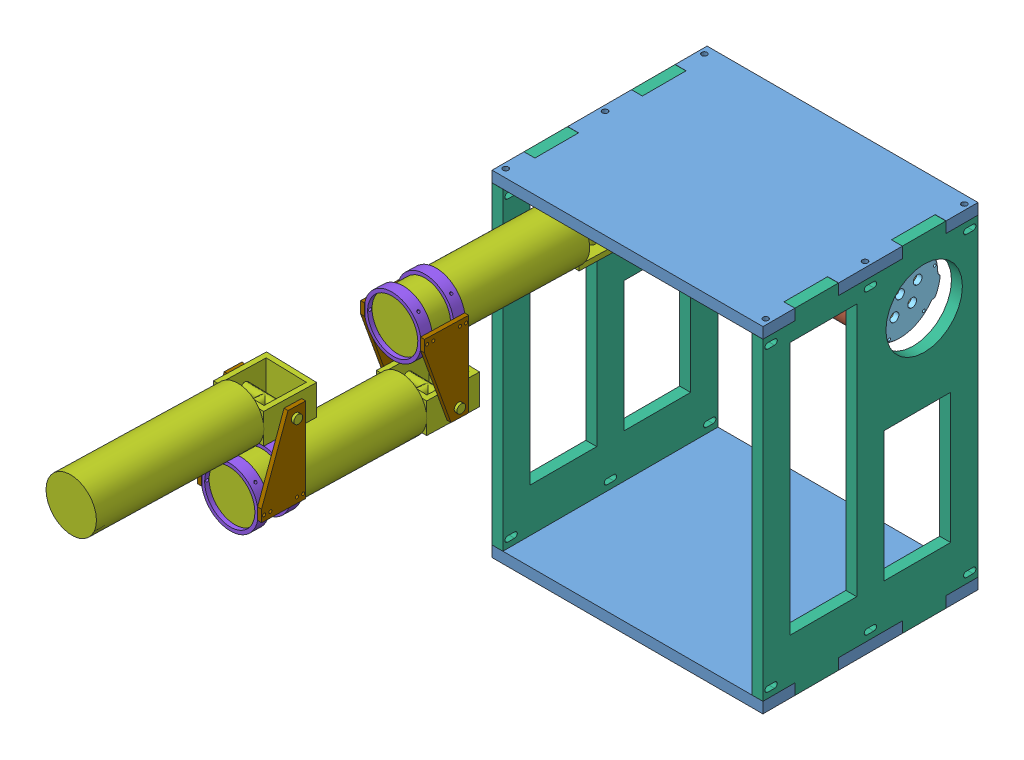
SolidWorks assembly EnsamblajeRobotC_Movimiento_Long, configuration Predeterminado. Lengths in mm.
Overall size (320.46 390 780.45).
23 component instances, 9 part files, 18 mates.
Components (placement in the parent):
- TP_Base-1: TP_Base [Predeterminado] at origin size (315 12.7 250)
- EnsambleTubo-1: EnsambleTubo [Predeterminado] at (117.3931 -62.5 -62.4) x (1 0 0) z (0 0.206267 0.978496) size (292.35 100.44 103.58)
  - WTE3-P-LOCKING-TUBE-240-R2-1: WTE3-P-LOCKING-TUBE-240-R2 [Predeterminado] at origin size (240.01 88.9 88.9)
  - WTE3-M-LOCKING-FLANGE-SEAL-R1-RP-1: WTE3-M-LOCKING-FLANGE-SEAL-R1-RP [Predeterminado] at (-21 0 0) x (0 0 -1) z (1 0 0) size (88.9 95.83 27.56)
  - WTE3-M-LOCKING-FLANGE-SEAL-R1-RP-2: WTE3-M-LOCKING-FLANGE-SEAL-R1-RP [Predeterminado] at (-219 0 0) x (0 0 1) z (-1 0 0) size (88.9 95.83 27.56)
  - WTE3-P-DOME-R1-1: WTE3-P-DOME-R1 [Default] at (-246 0 0) x (0 0.996902 0.078658) z (0 -0.078658 0.996902) size (79.25 34.35 79.25)
  - WTE3-M-END-CAP-7-HOLE-R1-1: WTE3-M-END-CAP-7-HOLE-R1 [Default] at (6 0 0) x (0 -0.102065 -0.994778) z (1 0 0) size (95 88.9 6)
- TP_Base-2: TP_Base [Predeterminado] at (0 -377.3 0.1) size (315 12.7 250)
- Side_Base_Long-1: Side_Base_Long [Predeterminado] at (-157.5 -182.3 0.1) x (0 0 -1) z (1 0 0) size (250 390 12.7)
- Side_Base_Long-2: Side_Base_Long [Predeterminado] at (144.8 -182.3 0.1) x (0 0 -1) z (1 0 0) size (250 390 12.7)
- EslabonVertical-1: EslabonVertical [Predeterminado] at (-104.5 -39.75 63) x (0 -1 0) z (-0.027267 0 0.999628) size (140.08 96.17 254.65)
  - EslabonSimplificado-1: EslabonSimplificado [Predeterminado] at origin size (79.5 60.33 249.5)
  - SujeccionMotorV2-1: SujeccionMotorV2 [Predeterminado] at (0 0 181) x (0.707107 -0.707107 0) z (0 0 1) size (68 68 12.7)
  - Soporte-1: Soporte [Predeterminado] at (-6.35 -38.1643 174.65) x (0 0 -1) z (0 1 0) size (50 98.35 4.76)
  - SujeccionMotorV2-2: SujeccionMotorV2 [Predeterminado] at (0 0 218.15) x (0.707107 -0.707107 0) z (0 0 1) size (68 68 12.7)
  - Soporte-2: Soporte [Predeterminado] at (-6.35 33.4018 174.65) x (0 0 -1) z (0 1 0) size (50 98.35 4.76)
- EslabonHorizontal-1: EslabonHorizontal [Predeterminado] at (-107.9866 -120.4 248.9741) x (0.999628 0 0.027267) z (-0.027267 0 0.999628) size (96.17 140.08 254.65)
  - EslabonSimplificado-1: EslabonSimplificado [Predeterminado] at origin size (79.5 60.33 249.5)
  - SujeccionMotorV2-1: SujeccionMotorV2 [Predeterminado] at (0 0 181) x (0.707107 0.707107 0) z (0 0 1) size (68 68 12.7)
  - Soporte-1: Soporte [Predeterminado] at (38.1643 -6.35 174.65) x (0 0 -1) z (-1 0 0) size (50 98.35 4.76)
  - SujeccionMotorV2-2: SujeccionMotorV2 [Predeterminado] at (0 0 218.15) x (0.707107 0.707107 0) z (0 0 1) size (68 68 12.7)
  - Soporte-2: Soporte [Predeterminado] at (-33.4018 -6.35 174.65) x (0 0 -1) z (-1 0 0) size (50 98.35 4.76)
- EslabonSimplificado-1: EslabonSimplificado [Predeterminado] at (-111.4732 -39.75 434.9482) x (0.999628 0 0.027267) z (-0.027267 0 0.999628) size (79.5 60.33 249.5)
Mates (geometry in assembly coordinates):
- Coincidente1: coincident anti-aligned: plane of TP_Base-1 through (-144.8 0 -87.9) normal (-1 0 0); plane of Side_Base_Long-1 through (-144.8 -182.3 0.1) normal (1 0 0)
- Coincidente2: coincident anti-aligned: plane of TP_Base-1 through (-157.5 0 -37.1) normal (0 0 -1); plane of Side_Base_Long-1 through (-157.5 12.7 -37.1) normal (0 0 1)
- Coincidente3: coincident aligned: plane of TP_Base-1 through (0 12.7 0) normal (0 1 0); plane of Side_Base_Long-1 through (-144.8 12.7 125.1) normal (0 1 0)
- Concéntrica1: concentric aligned: cylinder of EnsambleTubo-1/WTE3-P-LOCKING-TUBE-240-R2-1 through (41.1931 -62.5 -62.4) axis (-1 0 0) radius 44.45; cylinder of Side_Base_Long-1 through (-144.8 -62.5 -62.4) axis (-1 0 0) radius 44.5
- Coincidente4: coincident anti-aligned: plane of TP_Base-1 through (144.8 0 -87.9) normal (1 0 0); plane of Side_Base_Long-2 through (144.8 -182.3 0.1) normal (-1 0 0)
- Coincidente5: coincident anti-aligned: plane of TP_Base-1 through (157.5 0 87.9) normal (0 0 -1); plane of Side_Base_Long-2 through (144.8 12.7 87.9) normal (0 0 1)
- Coincidente6: coincident aligned: plane of TP_Base-1 through (0 12.7 0) normal (0 1 0); plane of Side_Base_Long-2 through (157.5 12.7 125.1) normal (0 1 0)
- Coincidente7: coincident anti-aligned: plane of TP_Base-2 through (0 -364.6 0.1) normal (0 1 0); plane of Side_Base_Long-2 through (144.8 -364.6 125.1) normal (0 -1 0)
- Coincidente8: coincident aligned: plane of TP_Base-2 through (157.5 -364.6 125.1) normal (1 0 0); plane of Side_Base_Long-2 through (157.5 -182.3 0.1) normal (1 0 0)
- Coincidente9: coincident aligned: plane of TP_Base-2 through (-157.5 -364.6 125.1) normal (0 0 1); plane of Side_Base_Long-2 through (157.5 -377.3 125.1) normal (0 0 1)
- Concéntrica2: concentric aligned: cylinder of TP_Base-1 through (-104.5 1 63) axis (0 -1 0) radius 5; cylinder of EslabonVertical-1/EslabonSimplificado-1 through (-104.5 23.25 63) axis (0 -1 0) radius 5
- Coincidente10: coincident anti-aligned: plane of TP_Base-1 through (0 0 0) normal (0 -1 0); plane of EslabonVertical-1/EslabonSimplificado-1 through (-104.5 0 63) normal (0 1 0)
- Concéntrica3: concentric anti-aligned: cylinder of EslabonVertical-1/Soporte-1 through (-142.9611 -120.4 248.0201) axis (-0.999628 0 -0.027267) radius 5; cylinder of EslabonHorizontal-1/EslabonSimplificado-1 through (-170.9632 -120.4 247.2562) axis (0.999628 0 0.027267) radius 5
- Coincidente11: coincident aligned: plane of EslabonVertical-1/Soporte-1 through (-147.4123 -33.4 236.5444) normal (-0.999628 0 -0.027267); plane of EslabonHorizontal-1/EslabonSimplificado-1 through (-147.7218 -120.4 247.8902) normal (-0.999628 0 -0.027267)
- Concéntrica4: concentric aligned: cylinder of EslabonHorizontal-1/Soporte-2 through (-151.2084 -39.75 433.8643) axis (0.999628 0 0.027267) radius 5; cylinder of EslabonSimplificado-1 through (-174.4498 -39.75 433.2303) axis (0.999628 0 0.027267) radius 5
- Coincidente12: coincident aligned: plane of EslabonHorizontal-1/Soporte-2 through (-150.8989 -126.75 422.5185) normal (-0.999628 0 -0.027267); plane of EslabonSimplificado-1 through (-151.2084 -39.75 433.8643) normal (-0.999628 0 -0.027267)
- Paralelo1: parallel anti-aligned: line of Side_Base_Long-2 through (157.5 0 125.1) axis (0 -1 0); line of EslabonHorizontal-1/EslabonSimplificado-1 through (-77.1797 -137.9 219.8033) axis (0 1 0)
- Paralelo2: parallel aligned: line of EslabonHorizontal-1/EslabonSimplificado-1 through (-77.1797 -137.9 219.8033) axis (0 1 0); line of EslabonSimplificado-1 through (-80.662 -56.973 405.6175) axis (-0.000251 0.999958 0.009207)
